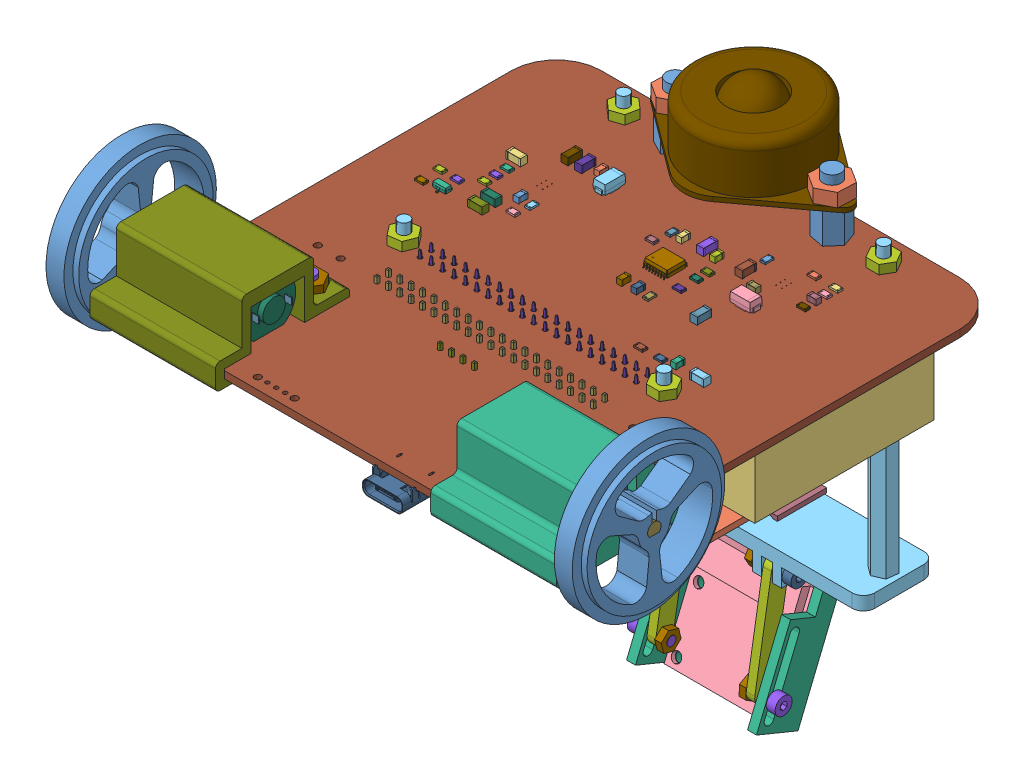
SolidWorks assembly car, configuration 默认. Lengths in mm.
Overall size (120 118.39 114.62).
182 component instances, 136 part files, 121 mates.
Components (placement in the parent):
- N20 wheel -1: N20 wheel  [默认] at (61.828 104.4 217.2679) x (0 0 1) z (0 -1 0) size (34 8.6 34)
- N20 wheel -2: N20 wheel  [默认] at (-58.172 104.4 217.2679) x (0 0 1) z (0 1 0) size (34 8.6 34)
- raspberrypi3.stp-1: raspberrypi3.stp [默认] at (-8.172 76.85 165.8679) x (-1 0 0) z (0 0 -1) size (90.89 18.8 58.5)
  - Raspberry Pi 3.stp-1: Raspberry Pi 3.stp [默认] at origin size (90.89 18.8 58.5)
    - Raspberry Pi 3_1.stp-1: Raspberry Pi 3_1.stp [默认] at origin size (85 1.3 56)
    - Raspberry Pi 3_1_1.stp-1: Raspberry Pi 3_1_1.stp [默认] at origin size (14 1 14)
    - Raspberry Pi 3_2.stp-1: Raspberry Pi 3_2.stp [默认] at origin size (8.5 1 8.5)
    - Raspberry Pi 3_3.stp-1: Raspberry Pi 3_3.stp [默认] at origin size (12 1 12)
    - Raspberry Pi 3_4.stp-1: Raspberry Pi 3_4.stp [默认] at origin size (0.64 10.23 0.64)
    - Raspberry Pi 3_5.stp-1: Raspberry Pi 3_5.stp [默认] at origin size (0.64 10.23 0.64)
    - Raspberry Pi 3_6.stp-1: Raspberry Pi 3_6.stp [默认] at origin size (0.64 10.23 0.64)
    - Raspberry Pi 3_7.stp-1: Raspberry Pi 3_7.stp [默认] at origin size (0.64 10.23 0.64)
    - Raspberry Pi 3_8.stp-1: Raspberry Pi 3_8.stp [默认] at origin size (0.64 10.23 0.64)
    - Raspberry Pi 3_9.stp-1: Raspberry Pi 3_9.stp [默认] at origin size (0.64 10.23 0.64)
    - Raspberry Pi 3_10.stp-1: Raspberry Pi 3_10.stp [默认] at origin size (0.64 10.23 0.64)
    - Raspberry Pi 3_11.stp-1: Raspberry Pi 3_11.stp [默认] at origin size (0.64 10.23 0.64)
    - Raspberry Pi 3_12.stp-1: Raspberry Pi 3_12.stp [默认] at origin size (0.64 10.23 0.64)
    - Raspberry Pi 3_13.stp-1: Raspberry Pi 3_13.stp [默认] at origin size (0.64 10.23 0.64)
    - Raspberry Pi 3_14.stp-1: Raspberry Pi 3_14.stp [默认] at origin size (0.64 10.23 0.64)
    - Raspberry Pi 3_15.stp-1: Raspberry Pi 3_15.stp [默认] at origin size (0.64 10.23 0.64)
    - Raspberry Pi 3_16.stp-1: Raspberry Pi 3_16.stp [默认] at origin size (0.64 10.23 0.64)
    - Raspberry Pi 3_17.stp-1: Raspberry Pi 3_17.stp [默认] at origin size (0.64 10.23 0.64)
    - Raspberry Pi 3_18.stp-1: Raspberry Pi 3_18.stp [默认] at origin size (0.64 10.23 0.64)
    - Raspberry Pi 3_19.stp-1: Raspberry Pi 3_19.stp [默认] at origin size (0.64 10.23 0.64)
    - Raspberry Pi 3_20.stp-1: Raspberry Pi 3_20.stp [默认] at origin size (0.64 10.23 0.64)
    - Raspberry Pi 3_21.stp-1: Raspberry Pi 3_21.stp [默认] at origin size (0.64 10.23 0.64)
    - Raspberry Pi 3_22.stp-1: Raspberry Pi 3_22.stp [默认] at origin size (0.64 10.23 0.64)
    - Raspberry Pi 3_23.stp-1: Raspberry Pi 3_23.stp [默认] at origin size (0.64 10.23 0.64)
    - Raspberry Pi 3_24.stp-1: Raspberry Pi 3_24.stp [默认] at origin size (0.64 10.23 0.64)
    - Raspberry Pi 3_25.stp-1: Raspberry Pi 3_25.stp [默认] at origin size (0.64 10.23 0.64)
    - Raspberry Pi 3_26.stp-1: Raspberry Pi 3_26.stp [默认] at origin size (0.64 10.23 0.64)
    - Raspberry Pi 3_27.stp-1: Raspberry Pi 3_27.stp [默认] at origin size (0.64 10.23 0.64)
    - Raspberry Pi 3_28.stp-1: Raspberry Pi 3_28.stp [默认] at origin size (0.64 10.23 0.64)
    - Raspberry Pi 3_29.stp-1: Raspberry Pi 3_29.stp [默认] at origin size (0.64 10.23 0.64)
    - Raspberry Pi 3_30.stp-1: Raspberry Pi 3_30.stp [默认] at origin size (0.64 10.23 0.64)
    - Raspberry Pi 3_31.stp-1: Raspberry Pi 3_31.stp [默认] at origin size (0.64 10.23 0.64)
    - Raspberry Pi 3_32.stp-1: Raspberry Pi 3_32.stp [默认] at origin size (0.64 10.23 0.64)
    - Raspberry Pi 3_33.stp-1: Raspberry Pi 3_33.stp [默认] at origin size (0.64 10.23 0.64)
    - Raspberry Pi 3_34.stp-1: Raspberry Pi 3_34.stp [默认] at origin size (0.64 10.23 0.64)
    - Raspberry Pi 3_35.stp-1: Raspberry Pi 3_35.stp [默认] at origin size (0.64 10.23 0.64)
    - Raspberry Pi 3_36.stp-1: Raspberry Pi 3_36.stp [默认] at origin size (0.64 10.23 0.64)
    - Raspberry Pi 3_37.stp-1: Raspberry Pi 3_37.stp [默认] at origin size (0.64 10.23 0.64)
    - Raspberry Pi 3_38.stp-1: Raspberry Pi 3_38.stp [默认] at origin size (0.64 10.23 0.64)
    - Raspberry Pi 3_39.stp-1: Raspberry Pi 3_39.stp [默认] at origin size (0.64 10.23 0.64)
    - Raspberry Pi 3_40.stp-1: Raspberry Pi 3_40.stp [默认] at origin size (0.64 10.23 0.64)
    - Raspberry Pi 3_41.stp-1: Raspberry Pi 3_41.stp [默认] at origin size (0.64 10.23 0.64)
    - Raspberry Pi 3_42.stp-1: Raspberry Pi 3_42.stp [默认] at origin size (0.64 10.23 0.64)
    - Raspberry Pi 3_43.stp-1: Raspberry Pi 3_43.stp [默认] at origin size (0.64 10.23 0.64)
    - Raspberry Pi 3_44.stp-1: Raspberry Pi 3_44.stp [默认] at origin size (50.8 2.54 5.08)
    - Raspberry Pi 3_45.stp-1: Raspberry Pi 3_45.stp [默认] at origin size (3.91 5.48 22.4)
    - Raspberry Pi 3_46.stp-1: Raspberry Pi 3_46.stp [默认] at origin size (14 1.3 13)
    - Raspberry Pi 3 (micro SD).stp-1: Raspberry Pi 3 (micro SD).stp [默认] at origin size (15 1 11)
    - Raspberry Pi 3_47.stp-1: Raspberry Pi 3_47.stp [默认] at origin size (17.3 15.6 13.3)
    - Raspberry Pi 3_48.stp-1: Raspberry Pi 3_48.stp [默认] at origin size (3.91 5.48 22.4)
    - Raspberry Pi 3_49.stp-1: Raspberry Pi 3_49.stp [默认] at origin size (7.9 2.25 5)
    - Raspberry Pi 3_50.stp-1: Raspberry Pi 3_50.stp [默认] at origin size (15 8.38 11.55)
    - Raspberry Pi 3_51.stp-1: Raspberry Pi 3_51.stp [默认] at origin size (7 9 15)
    - Raspberry Pi 3_52.stp-1: Raspberry Pi 3_52.stp [默认] at origin size (21.4 15.3 16.02)
    - Raspberry Pi 3_53.stp-1: Raspberry Pi 3_53.stp [默认] at origin size (17.3 15.6 13.3)
    - RPi Heatsink Set.stp-1: RPi Heatsink Set.stp [默认] at origin size (14 6 14)
    - RPi Heatsink Set_1.stp-1: RPi Heatsink Set_1.stp [默认] at origin size (8.8 5 8.8)
- M2.5 28+6-13: M2.5 28+6 [默认] at (30.828 69.4 135.1179) x (-0.540567 0 0.841301) z (-0.841301 0 -0.540567) size (4.87 34 5.26)
- M2.5 28+6-14: M2.5 28+6 [默认] at (30.828 69.4 184.1179) x (-0.717551 0 -0.696506) z (0.696506 0 -0.717551) size (4.87 34 5.26)
- M2.5 28+6-16: M2.5 28+6 [默认] at (-27.172 69.4 135.1179) size (4.87 34 5.26)
- M2.5 28+6-17: M2.5 28+6 [默认] at (-27.172 69.4 184.1179) size (4.87 34 5.26)
- N20 lift mounting-1: N20 lift mounting [默认] at (51.828 104.4 217.2679) x (0 0 -1) z (1 0 0) size (29.88 15.7 28)
- M2.5 nut-1: M2.5 nut [默认] at (30.828 101 135.1179) x (0.751714 0 -0.659489) z (0 -1 0) size (5.47 5.66 2)
- M3 8 hexagon socket head cap screw-1: M3 8 hexagon socket head cap screw [默认] at (48.828 92.7 205.2679) x (1 0 0.000001) z (0 1 0) size (5.5 5.5 11)
- M3 nut-1: M3 nut [默认] at (48.828 102.8 205.2679) x (-0.195277 0 -0.980748) z (0 -1 0) size (6.01 6.23 2.4)
- N20 motor-1: N20 motor [默认] at (27.828 104.4 217.2679) x (0 0 -1) z (0 1 0) size (12 35.5 10)
  - User Library-N20(2)-1: User Library-N20(2) [默认] at origin size (12 35.5 10)
    - User Library-N20_Pad010^User Library-N20(2)-1: User Library-N20_Pad010^User Library-N20(2) [默认] at (0 -23 0) x (1 0 0) z (0 -1 0) size (12 10 2) (virtual)
    - User Library-N20_Pad009^User Library-N20(2)-1: User Library-N20_Pad009^User Library-N20(2) [默认] at (0 -15 0) x (1 0 0) z (0 -1 0) size (12 10 8.5) (virtual)
    - User Library-N20_Pad008-1: User Library-N20_Pad008 [默认] at (0 -1 0) x (1 0 0) z (0 -1 0) size (12 10 33)
    - User Library-N20_Pad006^User Library-N20(2)-1: User Library-N20_Pad006^User Library-N20(2) [默认] at (0 -18 0) x (1 0 0) z (0 -1 0) size (12 10 1) (virtual)
    - User Library-N20_Pad004^User Library-N20(2)-1: User Library-N20_Pad004^User Library-N20(2) [默认] x (1 0 0) z (0 -1 0) size (7.5 1.5 1.5) (virtual)
    - User Library-N20_Pad003^User Library-N20(2)-1: User Library-N20_Pad003^User Library-N20(2) [默认] x (1 0 0) z (0 -1 0) size (12 10 2.2) (virtual)
- N20 motor-2: N20 motor [默认] at (-24.172 104.4 217.2679) x (0 0 -1) z (0 -1 0) size (12 35.5 10)
  - User Library-N20(2)-1: User Library-N20(2) [默认] at origin size (12 35.5 10)
    - User Library-N20_Pad010^User Library-N20(2)-1: User Library-N20_Pad010^User Library-N20(2) [默认] at (0 -23 0) x (1 0 0) z (0 -1 0) size (12 10 2) (virtual)
    - User Library-N20_Pad009^User Library-N20(2)-1: User Library-N20_Pad009^User Library-N20(2) [默认] at (0 -15 0) x (1 0 0) z (0 -1 0) size (12 10 8.5) (virtual)
    - User Library-N20_Pad008-1: User Library-N20_Pad008 [默认] at (0 -1 0) x (1 0 0) z (0 -1 0) size (12 10 33)
    - User Library-N20_Pad006^User Library-N20(2)-1: User Library-N20_Pad006^User Library-N20(2) [默认] at (0 -18 0) x (1 0 0) z (0 -1 0) size (12 10 1) (virtual)
    - User Library-N20_Pad004^User Library-N20(2)-1: User Library-N20_Pad004^User Library-N20(2) [默认] x (1 0 0) z (0 -1 0) size (7.5 1.5 1.5) (virtual)
    - User Library-N20_Pad003^User Library-N20(2)-1: User Library-N20_Pad003^User Library-N20(2) [默认] x (1 0 0) z (0 -1 0) size (12 10 2.2) (virtual)
- N20 right mounting-1: N20 right mounting [默认] at (-48.172 104.4 217.2679) x (0 0 -1) z (-1 0 0) size (29.88 15.7 28)
- M2.5 nut-2: M2.5 nut [默认] at (30.828 99 184.1179) x (-0.946991 0 0.321259) z (0 1 0) size (5.47 5.66 2)
- M3 8 hexagon socket head cap screw-2: M3 8 hexagon socket head cap screw [默认] at (-45.172 92.7 205.2679) x (-0.90696 0 -0.421216) z (0 1 0) size (5.5 5.5 11)
- M3 nut-2: M3 nut [默认] at (-45.172 102.8 205.2679) x (-0.195277 0 -0.980748) z (0 -1 0) size (6.01 6.23 2.4)
- M4 6 hexagon socket head cap screw-1: M4 6 hexagon socket head cap screw [默认] at (-15.622 97.4 135.1179) x (-0.248287 0 -0.968687) z (0 -1 0) size (7 7 10)
- ball wheel-1: ball wheel [默认] at (1.828 106 135.1179) x (0 0 1) z (-1 0 0) size (30.94 15 44.29)
- M4 7+6 copper cylinder-1: M4 7+6 copper cylinder [默认] at (-15.672 99 135.1179) x (-0.648514 0 -0.761203) z (0 1 0) size (6.41 6.87 13)
- M4 7+6 copper cylinder-2: M4 7+6 copper cylinder [默认] at (19.328 99 135.1179) x (-0.837169 0 -0.546944) z (0 1 0) size (6.41 6.87 13)
- M4 6 hexagon socket head cap screw-2: M4 6 hexagon socket head cap screw [默认] at (19.328 99 135.1179) x (-0.837169 0 -0.546944) z (0 -1 0) size (7 7 10)
- M4 nut-1: M4 nut [默认] at (-15.672 110 135.1179) x (1 0 0) z (0 -1 0) size (7.18 8.07 3)
- M4 nut-2: M4 nut [默认] at (19.328 110 135.1179) x (1 0 0) z (0 -1 0) size (7.18 8.07 3)
- M2.5 nut-3: M2.5 nut [默认] at (-27.172 101 135.1179) x (1 0 0) z (0 -1 0) size (5.47 5.66 2)
- M2.5 nut-4: M2.5 nut [默认] at (-27.172 99 184.1179) x (0.837169 0 0.546944) z (0 1 0) size (5.47 5.66 2)
- M2.5 28+6-18: M2.5 28+6 [默认] at (30.828 40.1 135.1179) size (4.87 34 5.26)
- M2.5 28+6-19: M2.5 28+6 [默认] at (-27.172 40.1 135.1179) x (0.98595 0 0.167042) z (-0.167042 0 0.98595) size (4.87 34 5.26)
- battery holder-1: battery holder [默认] at (7.8341 79.4 159.8679) x (1 0 0) z (0 1 0) size (87 40 18)
- camera-1: camera [默认] at (1.8346 15.6295 137.108) x (-1 0 0) z (0 0.379645 0.925132) size (25 24 7)
- camera base-1: camera base [默认] at (30.828 40.1 130.6179) x (-1 0 0) z (0 -1 0) size (65 16 7)
- camera holder 1-1: camera holder 1 [默认] at (26.3313 40.67 128.9941) x (1 0 0) z (0 0.379645 0.925132) size (28.99 34.4 10)
- camera holder 2-1: camera holder 2 [默认] at (26.328 40.3615 142.2656) x (1 0 0) z (0 0.164986 0.986296) size (24 26.6 4)
- M3 8 hexagon socket head cap screw-3: M3 8 hexagon socket head cap screw [默认] at (30.828 92.7 205.2679) x (-0.657725 0 0.753258) z (0 1 0) size (5.5 5.5 11)
- M3 nut-3: M3 nut [默认] at (30.828 100.4 205.2679) x (0.946991 0 -0.321259) z (0 1 0) size (6.01 6.23 2.4)
- M3 8 hexagon socket head cap screw-4: M3 8 hexagon socket head cap screw [默认] at (-27.172 92.7 205.2679) x (-0.942995 0 0.332807) z (0 1 0) size (5.5 5.5 11)
- M3 nut-4: M3 nut [默认] at (-27.172 102.8 205.2679) x (0.946991 0 0.321259) z (0 -1 0) size (6.01 6.23 2.4)
- M2 6 hexagon socket head cap screw-2: M2 6 hexagon socket head cap screw [默认] at (-12.6654 12.4152 144.9126) x (0 -0.106886 0.994271) z (-1 0 0) size (3.8 3.8 8)
- M2 6 hexagon socket head cap screw-3: M2 6 hexagon socket head cap screw [默认] at (16.328 12.4152 144.9126) x (0 0.878116 0.478448) z (1 0 0) size (3.8 3.8 8)
- M2 nut-1: M2 nut [默认] at (-6.7654 12.4152 144.9126) x (0 -0.106886 0.994271) z (-1 0 0) size (4.27 4.58 1.5)
- M2 nut-2: M2 nut [默认] at (10.4214 12.4152 144.9126) x (0 0.106886 -0.994271) z (1 0 0) size (4.27 4.58 1.5)
- M2 8 hexagon socket head cap screw-1: M2 8 hexagon socket head cap screw [默认] at (16.078 35.1 141.1179) x (0 0.16962 -0.98551) z (1 0 0) size (3.8 3.8 10)
- M2 8 hexagon socket head cap screw-2: M2 8 hexagon socket head cap screw [默认] at (18.578 35.1 129.1179) x (0 0.407507 0.913202) z (1 0 0) size (3.8 3.8 10)
- M2 8 hexagon socket head cap screw-3: M2 8 hexagon socket head cap screw [默认] at (-12.422 35.1 141.1179) x (0 0.951681 0.307087) z (-1 0 0) size (3.8 3.8 10)
- M2 8 hexagon socket head cap screw-4: M2 8 hexagon socket head cap screw [默认] at (-14.922 35.1 129.1179) x (0 -0.503432 0.864035) z (-1 0 0) size (3.8 3.8 10)
- M2 nut-3: M2 nut [默认] at (-6.922 35.1 129.1179) x (0 -0.381881 0.924211) z (-1 0 0) size (4.27 4.58 1.5) (hidden)
- M2 nut-4: M2 nut [默认] at (8.078 35.1 141.1179) x (0 0.60945 -0.792824) z (1 0 0) size (4.27 4.58 1.5)
- M2 nut-5: M2 nut [默认] at (10.578 35.1 129.1179) x (0 -0.991331 -0.131387) z (1 0 0) size (4.27 4.58 1.5)
- M2 nut-6: M2 nut [默认] at (-5.922 35.1 141.1179) x (0 0.60945 -0.792824) z (1 0 0) size (4.27 4.58 1.5)
- car pcb-1: car pcb [默认] at (-48.172 97.4 229.1179) x (0 0 -1) z (0 -1 0) size (103.47 100 12.36)
  - car pcb(2)-1: car pcb(2) [默认] at origin size (100 100 12.36)
    - Board_Geoms-1: Board_Geoms [默认] at origin size (100 100 1.6)
      - Pcb-1: Pcb [默认] at (-97.365 149.231 0) size (100 100 1.6)
        - Open CASCADE STEP translator 7.3 1.1.1.1^Pcb-1: Open CASCADE STEP translator 7.3 1.1.1.1^Pcb [默认] at origin size (100 100 1.6) (virtual)
    - Step_Models-1: Step_Models [默认] at origin size (69.83 72.3 12.36)
      - Top-1: Top [默认] at origin size (69.83 50.8 11.64)
        - J6_PinHeader_2x20_P254mm_Vertical_5E973953-1: J6_PinHeader_2x20_P254mm_Vertical_5E973953 [默认] at (34.12 74.135 0) size (5.08 50.8 11.54)
        - D1_LED_0805_2012Metric_5E97381B-1: D1_LED_0805_2012Metric_5E97381B [默认] at (96.209 38.751 0) x (0 1 0) z (0 0 1) size (2 1.25 1.1)
        - D3_LED_0805_2012Metric_5E973846-1: D3_LED_0805_2012Metric_5E973846 [默认] at (96.182 57.3275 0) x (0 1 0) z (0 0 1) size (2 1.25 1.1)
        - D5_LED_0805_2012Metric_5E973871-1: D5_LED_0805_2012Metric_5E973871 [默认] at (96.218 51.946 0) x (0 -1 0) z (0 0 1) size (2 1.25 1.1)
        - J2_PinHeader_1x04_P254mm_Vertical_5E9738C1-1: J2_PinHeader_1x04_P254mm_Vertical_5E9738C1 [默认] at (28.278 53.434 0) size (2.54 10.16 11.54)
        - J5_PinSocket_2x20_P254mm_Vertical_5E975A58-1: J5_PinSocket_2x20_P254mm_Vertical_5E975A58 [默认] at (46.26 74.13 0) size (5.08 50.8 10.1)
        - R4_R_0805_2012Metric_5E99E94D-1: R4_R_0805_2012Metric_5E99E94D [默认] at (96.209 42.815 0) x (0 -1 0) z (0 0 1) size (2 1.2 0.45)
        - R18_R_0805_2012Metric_5E9C048F-1: R18_R_0805_2012Metric_5E9C048F [默认] at (96.182 61.059 0) x (0 -1 0) z (0 0 1) size (2 1.2 0.45)
        - R21_R_0805_2012Metric_5E973B6B-1: R21_R_0805_2012Metric_5E973B6B [默认] at (96.218 47.882 0) x (0 -1 0) z (0 0 1) size (2 1.2 0.45)
      - Bot-1: Bot [默认] at origin size (34.4 72.3 2.22)
        - C5_C_0805_2012Metric_5E97372B-1: C5_C_0805_2012Metric_5E97372B [默认] at (76.411 51.91 -1.6) x (1 0 0) z (0 0 -1) size (2 1.25 1.25)
        - R15_R_0805_2012Metric_5E973B05-1: R15_R_0805_2012Metric_5E973B05 [默认] at (81.491 78.453 -1.6) x (0 1 0) z (0 0 -1) size (2 1.2 0.45)
        - C1_C_1206_3216Metric_5E9736E7-1: C1_C_1206_3216Metric_5E9736E7 [默认] at (50.95 81.1 -1.6) x (0 1 0) z (0 0 -1) size (3.2 1.6 1.6)
        - C2_C_0805_2012Metric_5E9736F8-1: C2_C_0805_2012Metric_5E9736F8 [默认] at (51.5 75.6 -1.6) x (-1 0 0) z (0 0 -1) size (2 1.25 1.25)
        - C3_C_0805_2012Metric_5E973709-1: C3_C_0805_2012Metric_5E973709 [默认] at (76.411 59.403 -1.6) x (-1 0 0) z (0 0 -1) size (2 1.25 1.25)
        - C4_C_1206_3216Metric_5E97BBAC-1: C4_C_1206_3216Metric_5E97BBAC [默认] at (77.046 56.609 -1.6) x (-1 0 0) z (0 0 -1) size (3.2 1.6 1.6)
        - C6_C_0805_2012Metric_5E97B6B1-1: C6_C_0805_2012Metric_5E97B6B1 [默认] at (61.552 53.434 -1.6) x (-1 0 0) z (0 0 -1) size (2 1.25 1.25)
        - C7_C_0805_2012Metric_5E97374D-1: C7_C_0805_2012Metric_5E97374D [默认] at (61.552 56.736 -1.6) x (1 0 0) z (0 0 -1) size (2 1.25 1.25)
        - C8_C_1206_3216Metric_5E97375E-1: C8_C_1206_3216Metric_5E97375E [默认] at (77.046 65.245 -1.6) x (1 0 0) z (0 0 -1) size (3.2 1.6 1.6)
        - C9_C_0805_2012Metric_5E97376F-1: C9_C_0805_2012Metric_5E97376F [默认] at (74.506 69.563 -1.6) x (0 -1 0) z (0 0 -1) size (2 1.25 1.25)
        - C10_C_0805_2012Metric_5E973780-1: C10_C_0805_2012Metric_5E973780 [默认] at (79.078 78.453 -1.6) x (0 1 0) z (0 0 -1) size (2 1.25 1.25)
        - C11_C_1206_3216Metric_5E973791-1: C11_C_1206_3216Metric_5E973791 [默认] at (63.076 69.182 -1.6) x (1 0 0) z (0 0 -1) size (3.2 1.6 1.6)
        - C12_C_1206_3216Metric_5E977737-1: C12_C_1206_3216Metric_5E977737 [默认] at (62.441 23.081 -1.6) x (0 1 0) z (0 0 -1) size (3.2 1.6 1.6)
        - C13_C_1206_3216Metric_5E978263-1: C13_C_1206_3216Metric_5E978263 [默认] at (59.52 23.081 -1.6) x (0 1 0) z (0 0 -1) size (3.2 1.6 1.6)
        - C14_C_1206_3216Metric_5E9737C4-1: C14_C_1206_3216Metric_5E9737C4 [默认] at (79.459 27.018 -1.6) x (-1 0 0) z (0 0 -1) size (3.2 1.6 1.6)
        - C15_C_1206_3216Metric_5E9737D5-1: C15_C_1206_3216Metric_5E9737D5 [默认] at (79.459 23.97 -1.6) x (-1 0 0) z (0 0 -1) size (3.2 1.6 1.6)
        - C16_C_0805_2012Metric_5E9737E6-1: C16_C_0805_2012Metric_5E9737E6 [默认] at (65.997 26.002 -1.6) x (-1 0 0) z (0 0 -1) size (2 1.25 1.25)
        - C17_C_0805_2012Metric_5E9737F7-1: C17_C_0805_2012Metric_5E9737F7 [默认] at (80.059 29.939 -1.6) x (-1 0 0) z (0 0 -1) size (2 1.25 1.25)
        - C18_C_1206_3216Metric_5E973808-1: C18_C_1206_3216Metric_5E973808 [默认] at (73.109 18.036 -1.6) x (0 -1 0) z (0 0 -1) size (3.2 1.6 1.6)
        - D2_D_SMA_5E9BCED4-1: D2_D_SMA_5E9BCED4 [默认] at (70.823 71.468 -1.6) x (0 -1 0) z (0 0 -1) size (5 2.7 2.22)
        - D4_D_SMA_5E9777E8-1: D4_D_SMA_5E9777E8 [默认] at (78.316 33.495 -1.6) x (-1 0 0) z (0 0 -1) size (5 2.7 2.22)
        - Q1_SOT_23_5E99EF72-1: Q1_SOT_23_5E99EF72 [默认] at (59.266 15.207 -1.6) x (-1 0 0) z (0 0 -1) size (2.5 3 1.2)
        - R1_R_0805_2012Metric_5E973A17-1: R1_R_0805_2012Metric_5E973A17 [默认] at (62.695 11.397 -1.6) x (0 1 0) z (0 0 -1) size (2 1.2 0.45)
        - R2_R_0805_2012Metric_5E973A28-1: R2_R_0805_2012Metric_5E973A28 [默认] at (62.695 15.207 -1.6) x (0 1 0) z (0 0 -1) size (2 1.2 0.45)
        - R3_R_0805_2012Metric_5E973A39-1: R3_R_0805_2012Metric_5E973A39 [默认] at (58.504 11.397 -1.6) x (0 -1 0) z (0 0 -1) size (2 1.2 0.45)
        - R5_R_0805_2012Metric_5E973A5B-1: R5_R_0805_2012Metric_5E973A5B [默认] at (50.75 72.5 -1.6) x (0 1 0) z (0 0 -1) size (2 1.2 0.45)
        - R6_R_0805_2012Metric_5E973A6C-1: R6_R_0805_2012Metric_5E973A6C [默认] at (50.7 68.1 -1.6) x (0 1 0) z (0 0 -1) size (2 1.2 0.45)
        - R7_R_0805_2012Metric_5E973A7D-1: R7_R_0805_2012Metric_5E973A7D [默认] at (61.552 59.276 -1.6) x (1 0 0) z (0 0 -1) size (2 1.2 0.45)
        - R8_R_0805_2012Metric_5E973A8E-1: R8_R_0805_2012Metric_5E973A8E [默认] at (72.728 48.608 -1.6) x (0 1 0) z (0 0 -1) size (2 1.2 0.45)
        - R9_R_0805_2012Metric_5E97BAD9-1: R9_R_0805_2012Metric_5E97BAD9 [默认] at (76.411 49.37 -1.6) x (-1 0 0) z (0 0 -1) size (2 1.2 0.45)
        - R10_R_0805_2012Metric_5E973AB0-1: R10_R_0805_2012Metric_5E973AB0 [默认] at (70.188 61.054 -1.6) x (0 -1 0) z (0 0 -1) size (2 1.2 0.45)
        - R11_R_0805_2012Metric_5E973AC1-1: R11_R_0805_2012Metric_5E973AC1 [默认] at (72.728 61.054 -1.6) x (0 1 0) z (0 0 -1) size (2 1.2 0.45)
        - R12_R_0805_2012Metric_5E97B756-1: R12_R_0805_2012Metric_5E97B756 [默认] at (66.378 61.054 -1.6) x (0 1 0) z (0 0 -1) size (2 1.2 0.45)
        - R13_R_0805_2012Metric_5E973AE3-1: R13_R_0805_2012Metric_5E973AE3 [默认] at (76.665 78.453 -1.6) x (0 1 0) z (0 0 -1) size (2 1.2 0.45)
        - R14_R_0805_2012Metric_5E973AF4-1: R14_R_0805_2012Metric_5E973AF4 [默认] at (81.745 65.245 -1.6) x (1 0 0) z (0 0 -1) size (2 1.2 0.45)
        - R16_R_0805_2012Metric_5E973B16-1: R16_R_0805_2012Metric_5E973B16 [默认] at (83.904 73.627 -1.6) x (0 1 0) z (0 0 -1) size (2 1.2 0.45)
        - R17_R_0805_2012Metric_5E973B27-1: R17_R_0805_2012Metric_5E973B27 [默认] at (83.904 78.453 -1.6) x (0 -1 0) z (0 0 -1) size (2 1.2 0.45)
        - R19_R_0805_2012Metric_5E973B49-1: R19_R_0805_2012Metric_5E973B49 [默认] at (62.568 27.78 -1.6) x (0 -1 0) z (0 0 -1) size (2 1.2 0.45)
        - R20_R_0805_2012Metric_5E973B5A-1: R20_R_0805_2012Metric_5E973B5A [默认] at (65.997 28.542 -1.6) x (1 0 0) z (0 0 -1) size (2 1.2 0.45)
        - R22_R_0805_2012Metric_5E973B7C-1: R22_R_0805_2012Metric_5E973B7C [默认] at (70.4133 18.636 -1.6) x (0 -1 0) z (0 0 -1) size (2 1.2 0.45)
        - R23_R_0805_2012Metric_5E9785CC-1: R23_R_0805_2012Metric_5E9785CC [默认] at (65.362 18.636 -1.6) x (0 -1 0) z (0 0 -1) size (2 1.2 0.45)
        - R24_R_0805_2012Metric_5E973B9E-1: R24_R_0805_2012Metric_5E973B9E [默认] at (67.8877 18.636 -1.6) x (0 -1 0) z (0 0 -1) size (2 1.2 0.45)
        - U1_TSSOP_16_1EP_44x5mm_Pitch065mm_EP34x5mm_5E973BE1-1: U1_TSSOP_16_1EP_44x5mm_Pitch065mm_EP34x5mm_5E973BE1 [默认] at (69.172 55.085 -1.6) x (1 0 0) z (0 0 -1) size (5.3 5.3 1.6)
  - User Library-USB Type C Port (SMD Type)-1: User Library-USB Type C Port (SMD Type) [Default] at (3.827 64.702 1.605) x (0 -1 0) z (0 0 -1) size (8.94 7.9 4.2)
Mates (geometry in assembly coordinates):
- 同心11: concentric: cylinder of assembly; cylinder of assembly; cylinder of M2.5 28+6-13 through (30.828 103.4 135.1179) axis (0 -1 0) radius 1.25; cylinder of M2.5 nut-1 through (30.828 99 135.1179) axis (0 1 0) radius 1.25
- 重合31: coincident: plane of assembly; plane of assembly; plane of N20 lift mounting-1 through (53.828 95.7 217.2679) normal (0 -1 0); plane of M3 8 hexagon socket head cap screw-1 through (48.828 95.7 205.2679) normal (0 1 0)
- 同心13: concentric: cylinder of assembly; cylinder of assembly; cylinder of M3 8 hexagon socket head cap screw-1 through (48.828 103.7 205.2679) axis (0 -1 0) radius 1.5; cylinder of M3 nut-1 through (48.828 100.4 205.2679) axis (0 1 0) radius 1.5
- 平行5: parallel: plane of assembly; plane of assembly; plane of N20 lift mounting-1 through (47.0959 111.4 208.2679) normal (0 0 -1); plane of M3 nut-1 through (50.4157 100.4 208.0179) normal (0 0 1)
- 重合41: coincident: plane of ? through (-8.172 69.4 131.6179) normal (0 1 0); plane of M2.5 28+6-17 through (-27.172 69.4 184.1179) normal (0 -1 0)
- 重合42: coincident: plane of ? through (-8.172 69.4 131.6179) normal (0 1 0); plane of M2.5 28+6-16 through (-27.172 69.4 135.1179) normal (0 -1 0)
- 重合43: coincident: plane of ? through (-8.172 69.4 131.6179) normal (0 1 0); plane of M2.5 28+6-13 through (30.828 69.4 135.1179) normal (0 -1 0)
- 重合44: coincident: plane of ? through (-8.172 69.4 131.6179) normal (0 1 0); plane of M2.5 28+6-14 through (30.828 69.4 184.1179) normal (0 -1 0)
- 重合45: coincident: plane of assembly; plane of assembly; plane of N20 lift mounting-1 through (51.828 104.4 217.2679) normal (-1 0 0); plane of N20 motor-1/User Library-N20(2)-1/User Library-N20_Pad010^User Library-N20(2)-1 through (51.828 99.4 222.2679) normal (1 0 0)
- 重合46: coincident: plane of assembly; plane of assembly; plane of N20 lift mounting-1 through (25.828 104.4 211.2679) normal (0 0 1); plane of N20 motor-1/User Library-N20(2)-1/User Library-N20_Pad010^User Library-N20(2)-1 through (50.828 100.4 211.2679) normal (0 0 -1)
- 重合48: coincident: plane of assembly; plane of assembly; plane of N20 wheel -1 through (55.228 103.4 218.386) normal (0 1 0); plane of N20 motor-1/User Library-N20(2)-1/User Library-N20_Pad008-1 through (53.828 103.4 217.2679) normal (0 -1 0)
- 同心21: concentric: cylinder of assembly; cylinder of assembly; cylinder of N20 wheel -1 through (55.228 104.4 217.2679) axis (1 0 0) radius 1.5; cylinder of N20 motor-1/User Library-N20(2)-1/User Library-N20_Pad008-1 through (42.828 104.4 217.2679) axis (-1 0 0) radius 1.5
- 重合49: coincident: plane of assembly; plane of assembly; plane of N20 wheel -1 through (61.828 104.4 217.2679) normal (1 0 0); plane of N20 motor-1/User Library-N20(2)-1/User Library-N20_Pad008-1 through (61.828 104.4 215.7679) normal (1 0 0)
- 重合58: coincident: plane of assembly; plane of assembly; plane of N20 wheel -2 through (-51.572 105.4 218.386) normal (0 -1 0); plane of N20 motor-2/User Library-N20(2)-1/User Library-N20_Pad008-1 through (-50.172 105.4 217.2679) normal (0 1 0)
- 同心22: concentric: cylinder of assembly; cylinder of assembly; cylinder of N20 wheel -2 through (-51.572 104.4 217.2679) axis (-1 0 0) radius 1.5; cylinder of N20 motor-2/User Library-N20(2)-1/User Library-N20_Pad008-1 through (-39.172 104.4 217.2679) axis (1 0 0) radius 1.5
- 重合59: coincident: plane of assembly; plane of assembly; plane of N20 wheel -2 through (-58.172 104.4 217.2679) normal (-1 0 0); plane of N20 motor-2/User Library-N20(2)-1/User Library-N20_Pad008-1 through (-58.172 104.4 215.7679) normal (-1 0 0)
- 重合63: coincident: plane of assembly; plane of assembly; plane of N20 right mounting-1 through (-50.172 95.7 217.2679) normal (0 -1 0); plane of M3 8 hexagon socket head cap screw-2 through (-45.172 95.7 205.2679) normal (0 1 0)
- 同心24: concentric: cylinder of assembly; cylinder of assembly; cylinder of M3 8 hexagon socket head cap screw-2 through (-45.172 103.7 205.2679) axis (0 -1 0) radius 1.5; cylinder of M3 nut-2 through (-45.172 100.4 205.2679) axis (0 1 0) radius 1.5
- 同心25: concentric: cylinder of assembly; cylinder of assembly; cylinder of M2.5 28+6-14 through (30.828 103.4 184.1179) axis (0 -1 0) radius 1.25; cylinder of M2.5 nut-2 through (30.828 101 184.1179) axis (0 -1 0) radius 1.25
- 同心27: concentric: cylinder of assembly; cylinder of assembly; cylinder of ball wheel-1 through (19.328 107 135.1179) axis (0 -1 0) radius 2; cylinder of M4 7+6 copper cylinder-2 through (19.328 112 135.1179) axis (0 -1 0) radius 2
- 重合69: coincident: plane of assembly; plane of assembly; plane of ball wheel-1 through (1.828 106 135.1179) normal (0 -1 0); plane of M4 7+6 copper cylinder-2 through (19.328 106 135.1179) normal (0 1 0)
- 同心32: concentric: cylinder of assembly; cylinder of assembly; cylinder of M4 7+6 copper cylinder-1 through (-15.672 112 135.1179) axis (0 -1 0) radius 2; cylinder of ball wheel-1 through (-15.672 107 135.1179) axis (0 -1 0) radius 2
- 重合71: coincident: plane of assembly; plane of assembly; plane of ball wheel-1 through (1.828 106 135.1179) normal (0 -1 0); plane of M4 7+6 copper cylinder-1 through (-15.672 106 135.1179) normal (0 1 0)
- 同心34: concentric: cylinder of assembly; cylinder of assembly; cylinder of M4 7+6 copper cylinder-2 through (19.328 103 135.1179) axis (0 -1 0) radius 2; cylinder of M4 6 hexagon socket head cap screw-2 through (19.328 105 135.1179) axis (0 -1 0) radius 2
- 同心35: concentric: cylinder of assembly; cylinder of assembly; cylinder of M4 7+6 copper cylinder-1 through (-15.672 112 135.1179) axis (0 -1 0) radius 2; cylinder of M4 nut-1 through (-15.672 107 135.1179) axis (0 1 0) radius 2
- 重合75: coincident: plane of assembly; plane of assembly; plane of ball wheel-1 through (1.828 107 135.1179) normal (0 1 0); plane of M4 nut-1 through (-15.672 107 135.1179) normal (0 -1 0)
- 同心36: concentric: cylinder of assembly; cylinder of assembly; cylinder of M4 7+6 copper cylinder-2 through (19.328 112 135.1179) axis (0 -1 0) radius 2; cylinder of M4 nut-2 through (19.328 107 135.1179) axis (0 1 0) radius 2
- 重合76: coincident: plane of assembly; plane of assembly; plane of ball wheel-1 through (1.828 107 135.1179) normal (0 1 0); plane of M4 nut-2 through (19.328 107 135.1179) normal (0 -1 0)
- 同心37: concentric: cylinder of assembly; cylinder of assembly; cylinder of M2.5 28+6-17 through (-27.172 103.4 184.1179) axis (0 -1 0) radius 1.25; cylinder of M2.5 nut-4 through (-27.172 101 184.1179) axis (0 -1 0) radius 1.25
- 同心38: concentric: cylinder of assembly; cylinder of assembly; cylinder of M2.5 28+6-16 through (-27.172 103.4 135.1179) axis (0 -1 0) radius 1.25; cylinder of M2.5 nut-3 through (-27.172 99 135.1179) axis (0 1 0) radius 1.25
- 同心40: concentric: cylinder of assembly; cylinder of assembly; cylinder of M2.5 28+6-16 through (-27.172 75.4 135.1179) axis (0 -1 0) radius 1.25; cylinder of M2.5 28+6-19 through (-27.172 74.1 135.1179) axis (0 -1 0) radius 1.25
- 重合80: coincident: plane of ? through (34.328 68.1 159.6179) normal (0 -1 0); plane of M2.5 28+6-19 through (-27.172 68.1 135.1179) normal (0 1 0)
- 同心41: concentric: cylinder of assembly; cylinder of assembly; cylinder of M2.5 28+6-13 through (30.828 75.4 135.1179) axis (0 -1 0) radius 1.25; cylinder of M2.5 28+6-18 through (30.828 74.1 135.1179) axis (0 -1 0) radius 1.25
- 重合81: coincident: plane of ? through (34.328 68.1 159.6179) normal (0 -1 0); plane of M2.5 28+6-18 through (30.828 68.1 135.1179) normal (0 1 0)
- 同心44: concentric: cylinder of assembly; cylinder of assembly; cylinder of camera-1 through (-8.6654 6.7578 141.8296) axis (0 -0.379645 -0.925132) radius 1.1; cylinder of camera holder 1-1 through (-8.6654 6.3782 140.9045) axis (0 -0.379645 -0.925132) radius 1
- 平行11: parallel: plane of assembly; plane of assembly; plane of camera-1 through (14.3346 4.9076 142.5889) normal (0 -0.925132 0.379645); plane of camera holder 1-1 through (16.328 3.9964 139.72) normal (0 -0.925132 0.379645)
- 重合111: coincident: plane of assembly; plane of assembly; plane of camera-1 through (1.8346 15.6295 137.108) normal (0 -0.379645 -0.925132); plane of camera holder 1-1 through (26.3313 39.9107 127.1438) normal (0 0.379645 0.925132)
- 重合112: coincident: plane of assembly; plane of assembly; plane of camera-1 through (1.8346 15.6295 137.108) normal (0 -0.379645 -0.925132); plane of camera holder 1-1 through (26.3313 39.9107 127.1438) normal (0 0.379645 0.925132)
- 同心50: concentric: cylinder of assembly; cylinder of assembly; cylinder of camera base-1 through (-30.672 35.1 141.1179) axis (1 0 0) radius 1.1; cylinder of camera holder 2-1 through (-10.172 35.1 141.1179) axis (1 0 0) radius 1.1
- 同心51: concentric: cylinder of assembly; cylinder of assembly; cylinder of camera base-1 through (-30.672 35.1 141.1179) axis (1 0 0) radius 1.1; cylinder of camera holder 2-1 through (-10.172 35.1 141.1179) axis (1 0 0) radius 1.1
- 平行12: parallel: plane of assembly; plane of assembly; plane of camera holder 1-1 through (14.328 36.376 126.4325) normal (-1 0 0); plane of camera holder 2-1 through (13.828 39.7015 138.3204) normal (1 0 0)
- 相切1: tangent: plane of assembly; cylinder of assembly; plane of camera holder 1-1 through (-12.6654 41.7709 131.6769) normal (0 0.379645 0.925132); cylinder of camera holder 2-1 through (-10.172 12.4152 144.9126) axis (1 0 0) radius 1.1
- 距离6: distance = 0.25 mm: plane of assembly; plane of assembly; plane of camera holder 2-1 through (13.828 39.7015 138.3204) normal (1 0 0); plane of camera base-1 through (14.078 33.1 130.6179) normal (-1 0 0)
- 距离7: distance = 0.25 mm: plane of assembly; plane of assembly; plane of camera holder 1-1 through (14.328 36.376 126.4325) normal (-1 0 0); plane of camera base-1 through (14.078 33.1 130.6179) normal (1 0 0)
- LimitDistance1: limit distance = 9.4828 mm: cylinder of assembly; cylinder of assembly; cylinder of camera holder 2-1 through (-10.172 12.4152 144.9126) axis (1 0 0) radius 1.1; cylinder of camera holder 1-1 through (-12.6654 23.2233 140.4773) axis (1 0 0) radius 1.1
- 距离13: distance = 3 mm: plane of assembly; cylinder of assembly; plane of battery holder-1 through (-31.1659 97.4 179.8679) normal (0 0 1); cylinder of M2.5 28+6-17 through (-27.172 103.4 184.1179) axis (0 -1 0) radius 1.25
- 重合121: coincident: plane of assembly; plane of assembly; plane of M2.5 28+6-18 through (30.828 40.1 135.1179) normal (0 -1 0); plane of camera base-1 through (30.828 40.1 130.6179) normal (0 1 0)
- 同心54: concentric: cylinder of assembly; cylinder of assembly; cylinder of N20 lift mounting-1 through (48.828 95.7 205.2679) axis (0 1 0) radius 1.6; cylinder of M3 8 hexagon socket head cap screw-1 through (48.828 103.7 205.2679) axis (0 -1 0) radius 1.5
- 重合127: coincident: plane of assembly; plane of assembly; plane of N20 lift mounting-1 through (51.828 100.4 217.2679) normal (0 1 0); plane of M3 nut-1 through (48.828 100.4 205.2679) normal (0 -1 0)
- 重合128: coincident: plane of assembly; plane of assembly; plane of N20 right mounting-1 through (-48.172 100.4 217.2679) normal (0 1 0); plane of M3 nut-2 through (-45.172 100.4 205.2679) normal (0 -1 0)
- 平行19: parallel: plane of assembly; plane of assembly; plane of N20 right mounting-1 through (-48.172 100.4 208.2679) normal (0 0 -1); plane of M3 nut-2 through (-46.7597 100.4 202.5179) normal (0 0 -1)
- 同心56: concentric: cylinder of assembly; cylinder of assembly; cylinder of M2.5 28+6-19 through (-27.172 46.1 135.1179) axis (0 -1 0) radius 1.25; cylinder of camera base-1 through (-27.172 37.1 135.1179) axis (0 1 0) radius 1.3
- 同心57: concentric: cylinder of assembly; circle of assembly; cylinder of M2.5 28+6-18 through (30.828 46.1 135.1179) axis (0 -1 0) radius 1.25; circle of camera base-1
- 距离14: distance = 2 mm: plane of battery holder-1 through (-31.1659 97.4 139.8679) normal (-1 0 0); plane of ? through (-33.1659 77.05 133.8679) normal (1 0 0)
- 同心59: concentric: cylinder of ? through (-27.172 68.1 135.1179) axis (0 1 0) radius 1.25; cylinder of M2.5 28+6-19 through (-27.172 74.1 135.1179) axis (0 -1 0) radius 1.25
- 同心60: concentric: cylinder of ? through (30.828 68.1 184.1179) axis (0 1 0) radius 1.25; cylinder of M2.5 28+6-14 through (30.828 75.4 184.1179) axis (0 -1 0) radius 1.25
- 重合131: coincident: plane of assembly; plane of assembly; plane of N20 lift mounting-1 through (51.828 100.4 217.2679) normal (0 1 0); plane of M3 nut-3 through (30.828 100.4 205.2679) normal (0 -1 0)
- 平行21: parallel: plane of N20 lift mounting-1 through (32.56 111.4 202.2679) normal (0 0 1); plane of M3 nut-3 through (32.4157 102.8 202.5179) normal (0 0 -1)
- 同心63: concentric: cylinder of assembly; cylinder of assembly; cylinder of N20 right mounting-1 through (-27.172 95.7 205.2679) axis (0 1 0) radius 1.6; cylinder of M3 8 hexagon socket head cap screw-4 through (-27.172 103.7 205.2679) axis (0 -1 0) radius 1.5
- 重合134: coincident: plane of N20 right mounting-1 through (-50.172 95.7 217.2679) normal (0 -1 0); plane of M3 8 hexagon socket head cap screw-4 through (-27.172 95.7 205.2679) normal (0 1 0)
- 同心64: concentric: cylinder of M3 8 hexagon socket head cap screw-4 through (-27.172 103.7 205.2679) axis (0 -1 0) radius 1.5; cylinder of M3 nut-4 through (-27.172 100.4 205.2679) axis (0 1 0) radius 1.5
- 平行22: parallel: plane of N20 right mounting-1 through (-48.172 111.4 208.2679) normal (0 0 -1); plane of M3 nut-4 through (-28.7597 100.4 202.5179) normal (0 0 -1)
- 重合136: coincident: plane of N20 right mounting-1 through (-48.172 100.4 217.2679) normal (0 1 0); plane of M3 nut-4 through (-27.172 100.4 205.2679) normal (0 -1 0)
- 同心66: concentric: cylinder of assembly; cylinder of assembly; cylinder of camera holder 2-1 through (-10.172 12.4152 144.9126) axis (1 0 0) radius 1.1; cylinder of M2 6 hexagon socket head cap screw-2 through (-6.6654 12.4152 144.9126) axis (-1 0 0) radius 1
- 重合138: coincident: plane of camera holder 1-1 through (-12.6654 36.376 126.4325) normal (-1 0 0); plane of M2 6 hexagon socket head cap screw-2 through (-12.6654 12.4152 144.9126) normal (1 0 0)
- 同心67: concentric: cylinder of assembly; cylinder of assembly; cylinder of camera holder 2-1 through (-10.172 12.4152 144.9126) axis (1 0 0) radius 1.1; cylinder of M2 6 hexagon socket head cap screw-3 through (10.328 12.4152 144.9126) axis (1 0 0) radius 1
- 重合139: coincident: plane of camera holder 1-1 through (16.328 36.376 126.4325) normal (1 0 0); plane of M2 6 hexagon socket head cap screw-3 through (16.328 12.4152 144.9126) normal (-1 0 0)
- 同心68: concentric: cylinder of M2 6 hexagon socket head cap screw-2 through (-6.6654 12.4152 144.9126) axis (-1 0 0) radius 1; cylinder of M2 nut-1 through (-8.2654 12.4152 144.9126) axis (1 0 0) radius 1
- 重合140: coincident: plane of camera holder 2-1 through (-8.2654 39.7015 138.3204) normal (1 0 0); plane of M2 nut-1 through (-8.2654 12.4152 144.9126) normal (-1 0 0)
- 同心69: concentric: cylinder of M2 6 hexagon socket head cap screw-3 through (10.328 12.4152 144.9126) axis (1 0 0) radius 1; cylinder of M2 nut-2 through (11.9214 12.4152 144.9126) axis (-1 0 0) radius 1
- 重合141: coincident: plane of camera holder 2-1 through (11.9214 39.7015 138.3204) normal (-1 0 0); plane of M2 nut-2 through (11.9214 12.4152 144.9126) normal (1 0 0)
- 重合142: coincident: plane of assembly; plane of assembly; plane of camera base-1 through (-14.922 33.1 130.6179) normal (-1 0 0); plane of M2 8 hexagon socket head cap screw-4 through (-14.922 35.1 129.1179) normal (1 0 0)
- 重合143: coincident: plane of assembly; plane of assembly; plane of camera base-1 through (18.578 33.1 130.6179) normal (1 0 0); plane of M2 8 hexagon socket head cap screw-2 through (18.578 35.1 129.1179) normal (-1 0 0)
- 同心73: concentric: cylinder of assembly; cylinder of assembly; cylinder of camera holder 2-1 through (-10.172 35.1 141.1179) axis (1 0 0) radius 1.1; cylinder of M2 8 hexagon socket head cap screw-1 through (8.078 35.1 141.1179) axis (1 0 0) radius 1
- 重合144: coincident: plane of camera base-1 through (16.078 33.1 130.6179) normal (1 0 0); plane of M2 8 hexagon socket head cap screw-1 through (16.078 35.1 141.1179) normal (-1 0 0)
- 同心74: concentric: cylinder of assembly; cylinder of assembly; cylinder of camera holder 2-1 through (-10.172 35.1 141.1179) axis (1 0 0) radius 1.1; cylinder of M2 8 hexagon socket head cap screw-3 through (-4.422 35.1 141.1179) axis (-1 0 0) radius 1
- 重合145: coincident: plane of camera base-1 through (-12.422 33.1 130.6179) normal (-1 0 0); plane of M2 8 hexagon socket head cap screw-3 through (-12.422 35.1 141.1179) normal (1 0 0)
- 同心75: concentric: cylinder of M2 8 hexagon socket head cap screw-4 through (-6.922 35.1 129.1179) axis (-1 0 0) radius 1; cylinder of M2 nut-3 through (-8.422 35.1 129.1179) axis (1 0 0) radius 1
- 重合146: coincident: plane of camera base-1 through (-8.422 33.1 130.6179) normal (1 0 0); plane of M2 nut-3 through (-8.422 35.1 129.1179) normal (-1 0 0)
- 同心77: concentric: cylinder of M2 8 hexagon socket head cap screw-2 through (10.578 35.1 129.1179) axis (1 0 0) radius 1; cylinder of M2 nut-5 through (12.078 35.1 129.1179) axis (-1 0 0) radius 1
- 重合147: coincident: plane of camera base-1 through (12.078 33.1 130.6179) normal (-1 0 0); plane of M2 nut-5 through (12.078 35.1 129.1179) normal (1 0 0)
- 同心78: concentric: cylinder of M2 8 hexagon socket head cap screw-1 through (8.078 35.1 141.1179) axis (1 0 0) radius 1; cylinder of M2 nut-4 through (9.578 35.1 141.1179) axis (-1 0 0) radius 1
- 重合148: coincident: plane of camera base-1 through (9.578 33.1 130.6179) normal (-1 0 0); plane of M2 nut-4 through (9.578 35.1 141.1179) normal (1 0 0)
- 同心79: concentric: cylinder of M2 8 hexagon socket head cap screw-3 through (-4.422 35.1 141.1179) axis (-1 0 0) radius 1; cylinder of M2 nut-6 through (-4.422 35.1 141.1179) axis (-1 0 0) radius 1
- 重合149: coincident: plane of camera base-1 through (-5.922 33.1 130.6179) normal (1 0 0); plane of M2 nut-6 through (-5.922 35.1 141.1179) normal (-1 0 0)
- 平行23: parallel: plane of camera base-1 through (30.828 37.1 130.6179) normal (0 -1 0); plane of M2 nut-6 through (-4.422 33.1 142.2726) normal (0 -1 0)
- 平行24: parallel: plane of camera base-1 through (30.828 37.1 130.6179) normal (0 -1 0); plane of M2 nut-3 through (-8.422 33.1 127.9632) normal (0 -1 0)
- 平行25: parallel: plane of camera base-1 through (30.828 37.1 130.6179) normal (0 -1 0); plane of M2 nut-5 through (12.078 33.1 130.2726) normal (0 -1 0)
- 平行26: parallel: plane of camera base-1 through (30.828 37.1 130.6179) normal (0 -1 0); plane of M2 nut-4 through (9.578 33.1 142.2726) normal (0 -1 0)
- 重合150: coincident: plane of assembly; plane of assembly; plane of N20 motor-1/User Library-N20(2)-1/User Library-N20_Pad010^User Library-N20(2)-1 through (51.828 99.4 222.2679) normal (1 0 0); plane of car pcb-1/car pcb(2)-1/Board_Geoms-1/Pcb-1/Open CASCADE STEP translator 7.3 1.1.1.1^Pcb-1 through (51.828 97.4 139.1179) normal (1 0 0)
- 重合151: coincident: plane of N20 lift mounting-1 through (25.828 97.4 217.2679) normal (0 1 0); plane of car pcb-1/car pcb(2)-1/Board_Geoms-1/Pcb-1/Open CASCADE STEP translator 7.3 1.1.1.1^Pcb-1 through (1.828 97.4 180.3057) normal (0 -1 0)
- 同心81: concentric: cylinder of M3 8 hexagon socket head cap screw-1 through (48.828 103.7 205.2679) axis (0 -1 0) radius 1.5; cylinder of car pcb-1/car pcb(2)-1/Board_Geoms-1/Pcb-1/Open CASCADE STEP translator 7.3 1.1.1.1^Pcb-1 through (48.828 97.4 205.2679) axis (0 -1 0) radius 1.6
- 重合152: coincident: plane of N20 right mounting-1 through (-22.172 97.4 217.2679) normal (0 1 0); plane of car pcb-1/car pcb(2)-1/Board_Geoms-1/Pcb-1/Open CASCADE STEP translator 7.3 1.1.1.1^Pcb-1 through (1.828 97.4 180.3057) normal (0 -1 0)
- 重合153: coincident: plane of N20 motor-2/User Library-N20(2)-1/User Library-N20_Pad010^User Library-N20(2)-1 through (-48.172 109.4 222.2679) normal (-1 0 0); plane of car pcb-1/car pcb(2)-1/Board_Geoms-1/Pcb-1/Open CASCADE STEP translator 7.3 1.1.1.1^Pcb-1 through (-48.172 97.4 139.1179) normal (-1 0 0)
- 同心82: concentric: cylinder of M3 8 hexagon socket head cap screw-2 through (-45.172 103.7 205.2679) axis (0 -1 0) radius 1.5; cylinder of car pcb-1/car pcb(2)-1/Board_Geoms-1/Pcb-1/Open CASCADE STEP translator 7.3 1.1.1.1^Pcb-1 through (-45.172 97.4 205.2679) axis (0 -1 0) radius 1.6
- 同心87: concentric: cylinder of assembly; cylinder of assembly; cylinder of N20 right mounting-1 through (-45.172 95.7 205.2679) axis (0 1 0) radius 1.6; cylinder of M3 8 hexagon socket head cap screw-2 through (-45.172 103.7 205.2679) axis (0 -1 0) radius 1.5
- 同心89: concentric: cylinder of M2.5 28+6-13 through (30.828 103.4 135.1179) axis (0 -1 0) radius 1.25; cylinder of car pcb-1/car pcb(2)-1/Board_Geoms-1/Pcb-1/Open CASCADE STEP translator 7.3 1.1.1.1^Pcb-1 through (30.828 97.4 135.1179) axis (0 -1 0) radius 1.35
- 同心90: concentric: cylinder of M2.5 28+6-17 through (-27.172 103.4 184.1179) axis (0 -1 0) radius 1.25; cylinder of car pcb-1/car pcb(2)-1/Board_Geoms-1/Pcb-1/Open CASCADE STEP translator 7.3 1.1.1.1^Pcb-1 through (-27.172 97.4 184.1179) axis (0 -1 0) radius 1.35
- 重合154: coincident: plane of M2.5 28+6-17 through (-27.172 97.4 184.1179) normal (0 1 0); plane of car pcb-1/car pcb(2)-1/Board_Geoms-1/Pcb-1/Open CASCADE STEP translator 7.3 1.1.1.1^Pcb-1 through (1.828 97.4 180.3057) normal (0 -1 0)
- 同心91: concentric: cylinder of M4 6 hexagon socket head cap screw-2 through (19.328 105 135.1179) axis (0 -1 0) radius 2; cylinder of car pcb-1/car pcb(2)-1/Board_Geoms-1/Pcb-1/Open CASCADE STEP translator 7.3 1.1.1.1^Pcb-1 through (19.328 97.4 135.1179) axis (0 -1 0) radius 2.15
- 同心92: concentric: cylinder of M4 6 hexagon socket head cap screw-1 through (-15.622 103.4 135.1179) axis (0 -1 0) radius 2; cylinder of car pcb-1/car pcb(2)-1/Board_Geoms-1/Pcb-1/Open CASCADE STEP translator 7.3 1.1.1.1^Pcb-1 through (-15.622 97.4 135.1179) axis (0 -1 0) radius 2.15
- 重合155: coincident: plane of M4 7+6 copper cylinder-2 through (19.328 99 135.1179) normal (0 -1 0); plane of car pcb-1/car pcb(2)-1/Board_Geoms-1/Pcb-1/Open CASCADE STEP translator 7.3 1.1.1.1^Pcb-1 through (1.828 99 180.3057) normal (0 1 0)
- 重合156: coincident: plane of M2.5 nut-4 through (-27.172 99 184.1179) normal (0 -1 0); plane of car pcb-1/car pcb(2)-1/Board_Geoms-1/Pcb-1/Open CASCADE STEP translator 7.3 1.1.1.1^Pcb-1 through (1.828 99 180.3057) normal (0 1 0)
- 重合157: coincident: plane of M2.5 nut-2 through (30.828 99 184.1179) normal (0 -1 0); plane of car pcb-1/car pcb(2)-1/Board_Geoms-1/Pcb-1/Open CASCADE STEP translator 7.3 1.1.1.1^Pcb-1 through (1.828 99 180.3057) normal (0 1 0)
- 重合158: coincident: plane of M2.5 nut-1 through (30.828 99 135.1179) normal (0 -1 0); plane of car pcb-1/car pcb(2)-1/Board_Geoms-1/Pcb-1/Open CASCADE STEP translator 7.3 1.1.1.1^Pcb-1 through (1.828 99 180.3057) normal (0 1 0)
- 重合159: coincident: plane of M2.5 nut-3 through (-27.172 99 135.1179) normal (0 -1 0); plane of car pcb-1/car pcb(2)-1/Board_Geoms-1/Pcb-1/Open CASCADE STEP translator 7.3 1.1.1.1^Pcb-1 through (1.828 99 180.3057) normal (0 1 0)
- 同心93: concentric: cylinder of ? through (30.828 68.1 135.1179) axis (0 1 0) radius 1.25; cylinder of M2.5 28+6-18 through (30.828 74.1 135.1179) axis (0 -1 0) radius 1.25
- 同心94: concentric: cylinder of ? through (-27.172 68.1 184.1179) axis (0 1 0) radius 1.25; cylinder of M2.5 28+6-17 through (-27.172 75.4 184.1179) axis (0 -1 0) radius 1.25
- 重合160: coincident: plane of camera base-1 through (-14.922 33.1 130.6179) normal (-1 0 0); plane of M2 8 hexagon socket head cap screw-4 through (-14.922 35.1 129.1179) normal (1 0 0)
- 同心95: concentric: cylinder of camera base-1 through (-30.672 35.1 129.1179) axis (1 0 0) radius 1.1; cylinder of M2 8 hexagon socket head cap screw-4 through (-6.922 35.1 129.1179) axis (-1 0 0) radius 1
- 同心96: concentric: cylinder of camera holder 1-1 through (-12.6654 35.1 129.1179) axis (1 0 0) radius 1.1; cylinder of M2 8 hexagon socket head cap screw-4 through (-6.922 35.1 129.1179) axis (-1 0 0) radius 1
- 重合161: coincident: plane of camera base-1 through (18.578 33.1 130.6179) normal (1 0 0); plane of M2 8 hexagon socket head cap screw-2 through (18.578 35.1 129.1179) normal (-1 0 0)
- 同心97: concentric: cylinder of camera base-1 through (-30.672 35.1 129.1179) axis (1 0 0) radius 1.1; cylinder of M2 8 hexagon socket head cap screw-2 through (10.578 35.1 129.1179) axis (1 0 0) radius 1
- 重合162: coincident: plane of M4 6 hexagon socket head cap screw-1 through (-15.622 97.4 135.1179) normal (0 1 0); plane of car pcb-1/car pcb(2)-1/Board_Geoms-1/Pcb-1/Open CASCADE STEP translator 7.3 1.1.1.1^Pcb-1 through (1.828 97.4 180.3057) normal (0 -1 0)
- 重合163: coincident: plane of battery holder-1 through (7.8341 97.4 159.8679) normal (0 1 0); plane of car pcb-1/car pcb(2)-1/Board_Geoms-1/Pcb-1/Open CASCADE STEP translator 7.3 1.1.1.1^Pcb-1 through (1.828 97.4 180.3057) normal (0 -1 0)
- 同心98: concentric: cylinder of assembly; cylinder of assembly; cylinder of N20 lift mounting-1 through (30.828 95.7 205.2679) axis (0 1 0) radius 1.6; cylinder of M3 8 hexagon socket head cap screw-3 through (30.828 103.7 205.2679) axis (0 -1 0) radius 1.5
- 重合164: coincident: plane of N20 lift mounting-1 through (53.828 95.7 217.2679) normal (0 -1 0); plane of M3 8 hexagon socket head cap screw-3 through (30.828 95.7 205.2679) normal (0 1 0)
- 同心99: concentric: cylinder of M3 8 hexagon socket head cap screw-3 through (30.828 103.7 205.2679) axis (0 -1 0) radius 1.5; cylinder of M3 nut-3 through (30.828 102.8 205.2679) axis (0 -1 0) radius 1.5
- 重合165: coincident: plane of N20 right mounting-1 through (-22.172 97.4 217.2679) normal (0 1 0); plane of car pcb-1/car pcb(2)-1/Board_Geoms-1/Pcb-1/Open CASCADE STEP translator 7.3 1.1.1.1^Pcb-1 through (1.828 97.4 180.3057) normal (0 -1 0)
- 重合166: coincident: plane of N20 lift mounting-1 through (25.828 97.4 217.2679) normal (0 1 0); plane of car pcb-1/car pcb(2)-1/Board_Geoms-1/Pcb-1/Open CASCADE STEP translator 7.3 1.1.1.1^Pcb-1 through (1.828 97.4 180.3057) normal (0 -1 0)
- 重合168: coincident: plane of assembly; plane of assembly; plane of N20 lift mounting-1 through (53.828 109.4 217.2679) normal (0 -1 0); plane of N20 motor-1/User Library-N20(2)-1/User Library-N20_Pad008-1 through (28.828 109.4 213.9513) normal (0 1 0)
